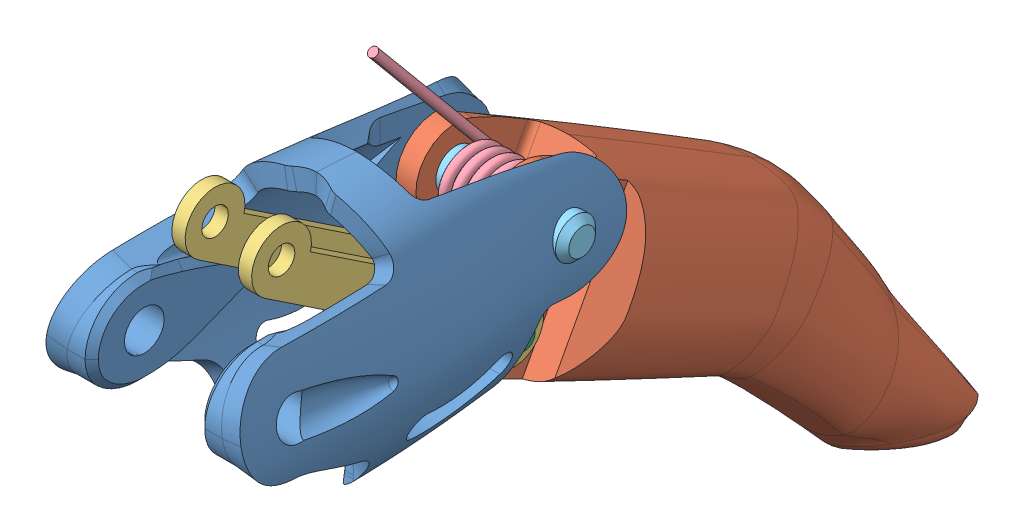
SolidWorks assembly 02-004, configuration 默认. Lengths in mm.
Overall size (17.27 44.34 67.28).
7 component instances, 6 part files, 12 mates.
Components (placement in the parent):
- 01-020-1: 01-020 [默认] at (11.7485 22.1596 51.7635) size (17.27 19.24 30.82)
- 01-021-1: 01-021 [默认] at (11.7485 22.3288 31.4662) x (1 0 0) z (0 0.476083 0.8794) size (12.29 17.46 47.7)
- 01-022-1: 01-022 [默认] at (13.7485 17.0357 26.9403) x (-1 0 0) z (0 -0.555199 -0.831718) size (1 6 26.5)
- 01-022-2: 01-022 [默认] at (8.7485 17.0357 26.9403) x (-1 0 0) z (0 -0.555199 -0.831718) size (1 6 26.5)
- 01-009-1: 01-009 [默认] at (9.8972 24.3818 25.8062) x (1 0 0) z (0 -0.633476 0.773762) size (5.44 18.26 4.7)
- 01-035-1: 01-035 [默认] at (4.7485 24.3818 25.8062) x (0 -0.984187 0.177132) z (-1 0 0) size (3 3 14)
- 01-036-1: 01-036 [默认] at (16.7485 17.0357 26.9403) x (0 -0.458162 -0.888869) z (1 0 0) size (2 2 7.6)
Mates (geometry in assembly coordinates):
- Concentric1: concentric anti-aligned: cylinder of 01-020-1 through (20.3864 24.3818 25.8062) axis (-1 0 0) radius 1.5; cylinder of 01-021-1 through (11.7435 24.3818 25.8062) axis (1 0 0) radius 1.5
- Concentric2: concentric aligned: cylinder of 01-020-1 through (20.3864 24.3818 25.8062) axis (-1 0 0) radius 1.5; cylinder of 01-035-1 through (4.7485 24.3818 25.8062) axis (-1 0 0) radius 1.5
- Width1: width aligned: plane of 01-035-1 through (18.7485 24.3818 25.8062) normal (1 0 0); plane of 01-035-1 through (4.7485 24.3818 25.8062) normal (-1 0 0); plane of 01-021-1 through (15.7485 13.9972 35.9767) normal (1 0 0); plane of 01-021-1 through (7.7485 13.9972 35.9767) normal (-1 0 0)
- Width2: width aligned: plane of 01-020-1 through (15.7485 22.13 29.4197) normal (-1 0 0); plane of 01-020-1 through (7.7485 22.13 29.4197) normal (1 0 0); plane of 01-021-1 through (7.7485 13.9972 35.9767) normal (-1 0 0); plane of 01-021-1 through (15.7485 13.9972 35.9767) normal (1 0 0)
- Coincident1: coincident anti-aligned: plane of 01-021-1 through (13.7485 21.5419 27.9122) normal (1 0 0); plane of 01-022-1 through (13.7485 17.0357 26.9403) normal (-1 0 0)
- Coincident2: coincident anti-aligned: plane of 01-021-1 through (9.7485 21.5419 27.9122) normal (-1 0 0); plane of 01-022-2 through (9.7485 17.0357 26.9403) normal (1 0 0)
- Concentric5: concentric aligned: cylinder of 01-022-1 through (14.7485 17.0357 26.9403) axis (-1 0 0) radius 1; cylinder of 01-036-1 through (6.7485 17.0357 26.9403) axis (-1 0 0) radius 1
- Concentric6: concentric aligned: cylinder of 01-022-1 through (14.7485 30.4977 44.4053) axis (-1 0 0) radius 1; cylinder of 01-022-2 through (9.7485 30.4977 44.4053) axis (-1 0 0) radius 1
- Lock1: lock: unknown of 01-020-1; unknown of 01-009-1
- Concentric7: concentric anti-aligned: cylinder of 01-021-1 through (9.7485 17.0357 26.9403) axis (1 0 0) radius 1; cylinder of 01-036-1 through (6.7485 17.0357 26.9403) axis (-1 0 0) radius 1
- Concentric8: concentric aligned: cylinder of 01-022-2 through (9.7485 17.0357 26.9403) axis (-1 0 0) radius 2.25; cylinder of 01-036-1 through (6.7485 17.0357 26.9403) axis (-1 0 0) radius 1
- Width3: width aligned: plane of 01-036-1 through (15.5485 16.6692 26.2292) normal (1 0 0); plane of 01-036-1 through (7.9485 16.6692 26.2292) normal (-1 0 0); plane of 01-022-1 through (14.7485 17.0357 26.9403) normal (1 0 0); plane of 01-022-2 through (8.7485 17.0357 26.9403) normal (-1 0 0)
